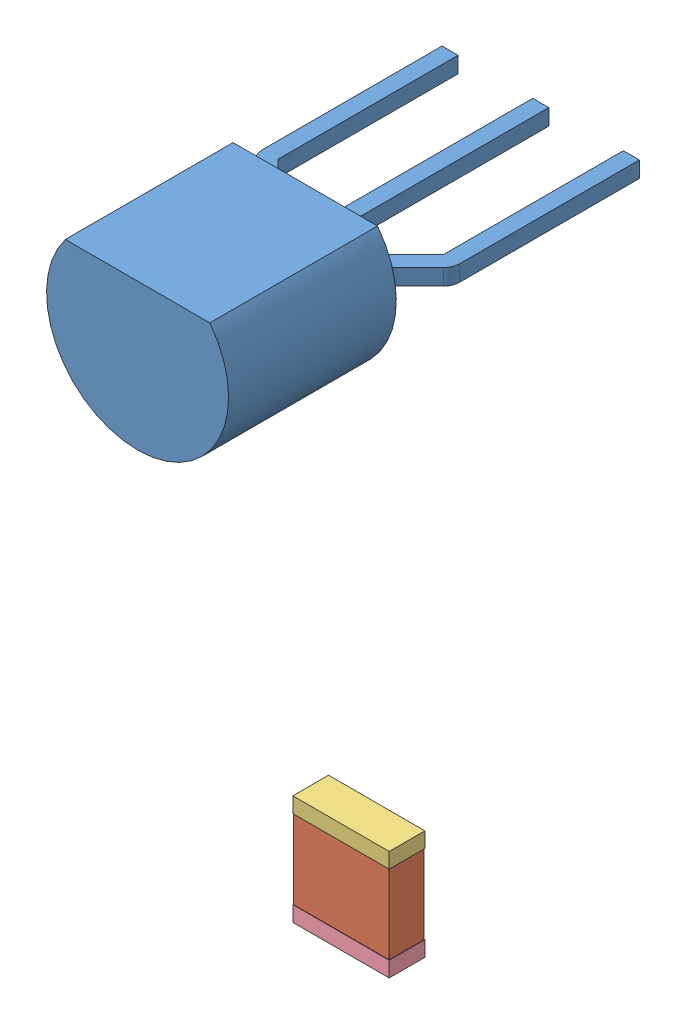
SolidWorks assembly temperature2, configuration Default. Lengths in mm.
Overall size (5.53 19.09 11.3).
8 component instances, 4 part files, 0 mates.
Components (placement in the parent):
- U2-1: U2 [Default] at (-17.5 20 0.775) x (-1 0 0) z (0 0 1) size (5.53 4.1 11.3)
  - Open CASCADE STEP translator 6.8 2.3.1-1: Open CASCADE STEP translator 6.8 2.3.1 [Default] at origin size (5.53 4.1 11.3)
    - Body_1_3-1: Body_1_3 [Default] at (0 0 2) x (-1 0 0) z (0 1 0) size (5.53 11.3 4.1)
- C1-1: C1 [Default] at (-17.5 5.5 0.775) x (0 -1 0) z (0 0 1) size (3.07 2.7 1)
  - Open CASCADE STEP translator 6.8 2.4.1-1: Open CASCADE STEP translator 6.8 2.4.1 [Default] at origin size (3.07 2.7 1)
    - Body_1_4-1: Body_1_4 [Default] at origin size (2.71 2.68 0.98)
    - Pin_1_2-1: Pin_1_2 [Default] at (0.36 0 0) x (-1 0 0) z (0 0 1) size (0.43 2.7 1)
    - Pin_2_2-1: Pin_2_2 [Default] at origin size (0.43 2.7 1)
